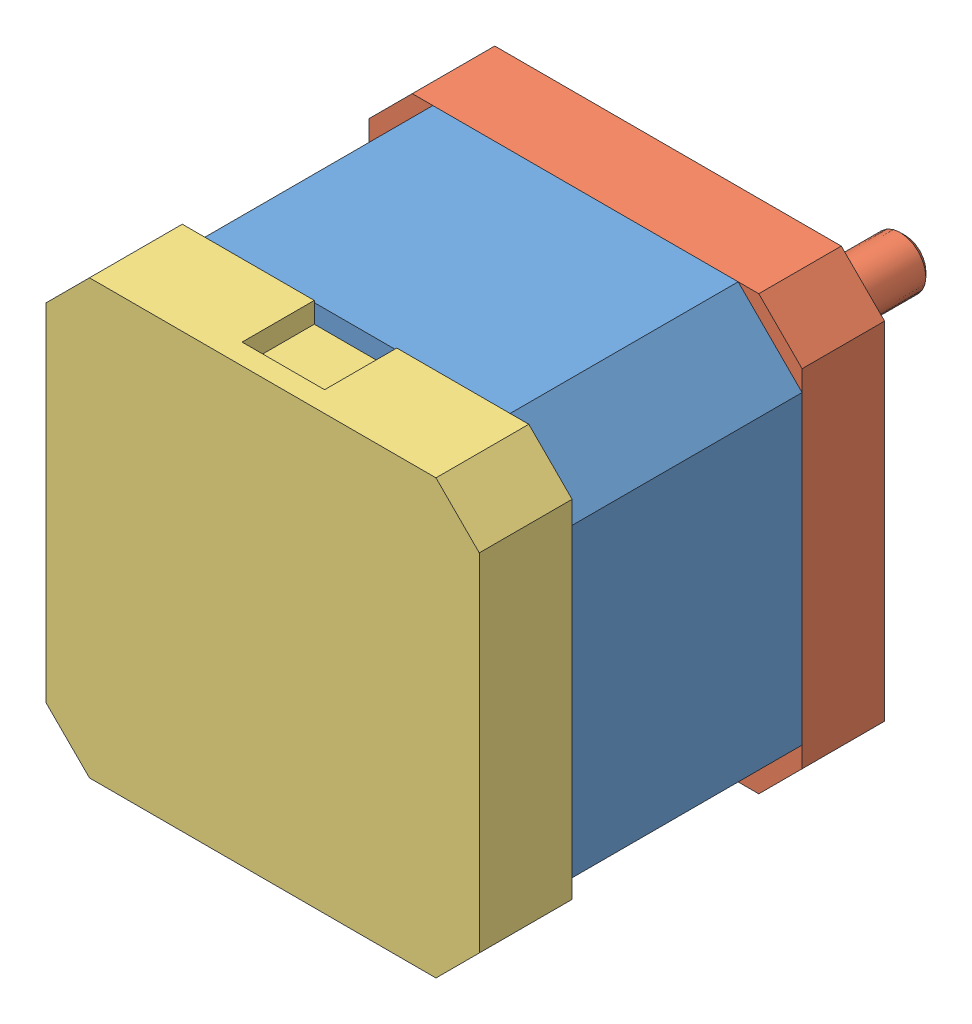
SolidWorks assembly NEMA_17_STEPPER_ASSEMBLY, configuration Valor predeterminado. Lengths in mm.
Overall size (42 42.19 62.3).
3 component instances, 3 part files, 0 mates.
Components (placement in the parent):
- STEPPER_PART_2-1: STEPPER_PART_2 [Valor predeterminado] at (-549.475 -32.5 22.825) x (0 -1 0) z (0 0 1) size (42 42 22.3)
- STEPPER_PART_3-1: STEPPER_PART_3 [Valor predeterminado] at (-549.475 -32.5 30.525) x (0 -1 0) z (0 0 1) size (42 42 31)
- STEPPER_PART_1-1: STEPPER_PART_1 [Valor predeterminado] at (-549.475 -32.3132 22.825) x (0 -1 0) z (0 0 1) size (42 42 9)
